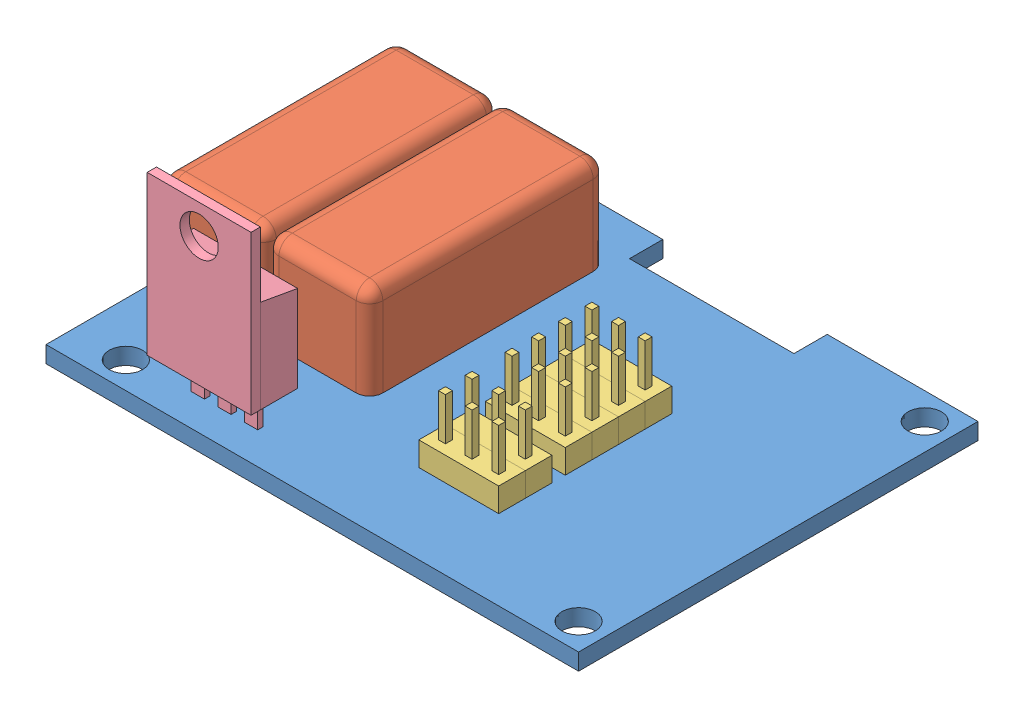
SolidWorks assembly Power Supply, configuration Default. Lengths in mm.
Overall size (50.8 20 38.1).
10 component instances, 4 part files, 29 mates.
Components (placement in the parent):
- PS Board-1: PS Board [Default] at (-5.9412 26.323 57.3693) size (50.8 1.59 38.1)
- LDD-700L-1: LDD-700L [Default] at (-0.9882 27.9105 35.2713) size (9.91 8.89 22.61)
- LDD-700L-2: LDD-700L [Default] at (9.1718 27.9105 35.2713) size (9.91 8.89 22.61)
- 1x3 Pin Header-1: 1x3 Pin Header [Default] at (25.8088 27.9105 34.5093) size (7.62 6.35 2.54)
- 1x3 Pin Header-2: 1x3 Pin Header [Default] at (25.8088 27.9105 37.0493) size (7.62 6.35 2.54)
- 1x3 Pin Header-3: 1x3 Pin Header [Default] at (25.8088 27.9105 48.4793) size (7.62 6.35 2.54)
- 1x3 Pin Header-4: 1x3 Pin Header [Default] at (25.8088 27.9105 39.5893) size (7.62 6.35 2.54)
- 1x3 Pin Header-5: 1x3 Pin Header [Default] at (25.8088 27.9105 45.9393) size (7.62 6.35 2.54)
- 1x3 Pin Header-6: 1x3 Pin Header [Default] at (25.8088 27.9105 42.1293) size (7.62 6.35 2.54)
- TO-220-1: TO-220 [Default] at (8.0288 27.9105 56.7343) x (-1 0 0) z (0 0 -1) size (9.91 18.41 4.45)
Mates (geometry in assembly coordinates):
- Coincident1: coincident anti-aligned: plane of PS Board-1 through (-5.9412 27.9105 57.3693) normal (0 1 0); plane of LDD-700L-1 through (-0.9882 27.9105 35.2713) normal (0 -1 0)
- Coincident2: coincident anti-aligned: plane of PS Board-1 through (-5.9412 27.9105 57.3693) normal (0 1 0); plane of LDD-700L-2 through (9.1718 27.9105 35.2713) normal (0 -1 0)
- Distance3: distance = 10.795 mm aligned: plane of LDD-700L-2 through (4.2188 36.8005 46.5743) normal (0 0 1); plane of PS Board-1 through (-5.9412 27.9105 57.3693) normal (0 0 1)
- Distance5: distance = 0 mm aligned: plane of LDD-700L-1 through (-5.9412 36.8005 23.9683) normal (-1 0 0); plane of PS Board-1 through (-5.9412 27.9105 57.3693) normal (-1 0 0)
- Coincident8: coincident aligned: plane of LDD-700L-1 through (-5.9412 36.8005 46.5743) normal (0 0 1); plane of LDD-700L-2 through (4.2188 36.8005 46.5743) normal (0 0 1)
- Distance6: distance = 10.16 mm aligned: plane of LDD-700L-2 through (4.2188 36.8005 23.9683) normal (-1 0 0); plane of PS Board-1 through (-5.9412 27.9105 57.3693) normal (-1 0 0)
- Coincident10: coincident anti-aligned: plane of PS Board-1 through (-5.9412 27.9105 57.3693) normal (0 1 0); plane of 1x3 Pin Header-6 through (25.8088 27.9105 42.1293) normal (0 -1 0)
- Coincident11: coincident anti-aligned: plane of PS Board-1 through (-5.9412 27.9105 57.3693) normal (0 1 0); plane of 1x3 Pin Header-5 through (25.8088 27.9105 45.9393) normal (0 -1 0)
- Coincident12: coincident anti-aligned: plane of PS Board-1 through (-5.9412 27.9105 57.3693) normal (0 1 0); plane of 1x3 Pin Header-4 through (25.8088 27.9105 39.5893) normal (0 -1 0)
- Coincident13: coincident anti-aligned: plane of PS Board-1 through (-5.9412 27.9105 57.3693) normal (0 1 0); plane of 1x3 Pin Header-3 through (25.8088 27.9105 48.4793) normal (0 -1 0)
- Coincident14: coincident anti-aligned: plane of PS Board-1 through (-5.9412 27.9105 57.3693) normal (0 1 0); plane of 1x3 Pin Header-2 through (25.8088 27.9105 37.0493) normal (0 -1 0)
- Coincident15: coincident anti-aligned: plane of PS Board-1 through (-5.9412 27.9105 57.3693) normal (0 1 0); plane of 1x3 Pin Header-1 through (25.8088 27.9105 34.5093) normal (0 -1 0)
- Coincident16: coincident aligned: plane of 1x3 Pin Header-1 through (29.6188 30.1965 33.2393) normal (1 0 0); plane of 1x3 Pin Header-2 through (29.6188 30.1965 35.7793) normal (1 0 0)
- Coincident17: coincident aligned: plane of 1x3 Pin Header-2 through (29.6188 30.1965 35.7793) normal (1 0 0); plane of 1x3 Pin Header-6 through (29.6188 30.1965 40.8593) normal (1 0 0)
- Coincident18: coincident aligned: plane of 1x3 Pin Header-5 through (29.6188 30.1965 44.6693) normal (1 0 0); plane of 1x3 Pin Header-6 through (29.6188 30.1965 40.8593) normal (1 0 0)
- Coincident19: coincident aligned: plane of 1x3 Pin Header-4 through (29.6188 30.1965 38.3193) normal (1 0 0); plane of 1x3 Pin Header-5 through (29.6188 30.1965 44.6693) normal (1 0 0)
- Coincident20: coincident aligned: plane of 1x3 Pin Header-3 through (29.6188 30.1965 47.2093) normal (1 0 0); plane of 1x3 Pin Header-4 through (29.6188 30.1965 38.3193) normal (1 0 0)
- Distance7: distance = 31.75 mm: line of 1x3 Pin Header-1 through (25.8088 32.7136 34.5093) axis (0 1 0); plane of PS Board-1 through (-5.9412 27.9105 57.3693) normal (-1 0 0)
- Distance8: distance = 22.86 mm: line of 1x3 Pin Header-1 through (25.8088 32.7136 34.5093) axis (0 1 0); plane of PS Board-1 through (-5.9412 27.9105 57.3693) normal (0 0 1)
- Parallel1: parallel aligned: plane of PS Board-1 through (44.8588 27.9105 57.3693) normal (1 0 0); plane of 1x3 Pin Header-2 through (29.6188 30.1965 35.7793) normal (1 0 0)
- Coincident24: coincident anti-aligned: plane of 1x3 Pin Header-1 through (21.9988 30.1965 35.7793) normal (0 0 1); plane of 1x3 Pin Header-2 through (21.9988 30.1965 35.7793) normal (0 0 -1)
- Coincident25: coincident anti-aligned: plane of 1x3 Pin Header-2 through (21.9988 30.1965 38.3193) normal (0 0 1); plane of 1x3 Pin Header-4 through (21.9988 30.1965 38.3193) normal (0 0 -1)
- Coincident26: coincident anti-aligned: plane of 1x3 Pin Header-4 through (21.9988 30.1965 40.8593) normal (0 0 1); plane of 1x3 Pin Header-6 through (21.9988 30.1965 40.8593) normal (0 0 -1)
- Coincident27: coincident anti-aligned: plane of 1x3 Pin Header-3 through (21.9988 30.1965 47.2093) normal (0 0 -1); plane of 1x3 Pin Header-5 through (21.9988 30.1965 47.2093) normal (0 0 1)
- Distance9: distance = 1.27 mm anti-aligned: plane of 1x3 Pin Header-6 through (21.9988 30.1965 43.3993) normal (0 0 1); plane of 1x3 Pin Header-5 through (21.9988 30.1965 44.6693) normal (0 0 -1)
- Coincident28: coincident: plane of PS Board-1 through (-5.9412 27.9105 57.3693) normal (0 1 0); plane of TO-220-1 through (8.0288 27.9105 54.7076) normal (0 -1 0)
- Parallel2: parallel: plane of PS Board-1 through (-5.9412 27.9105 57.3693) normal (0 0 1); plane of TO-220-1 through (8.0288 27.9105 56.7343) normal (0 0 1)
- Distance10: distance = 13.97 mm: point of TO-220-1; plane of PS Board-1 through (-5.9412 27.9105 57.3693) normal (-1 0 0)
- Distance11: distance = 0.635 mm: point of TO-220-1; plane of PS Board-1 through (-5.9412 27.9105 57.3693) normal (0 0 1)
